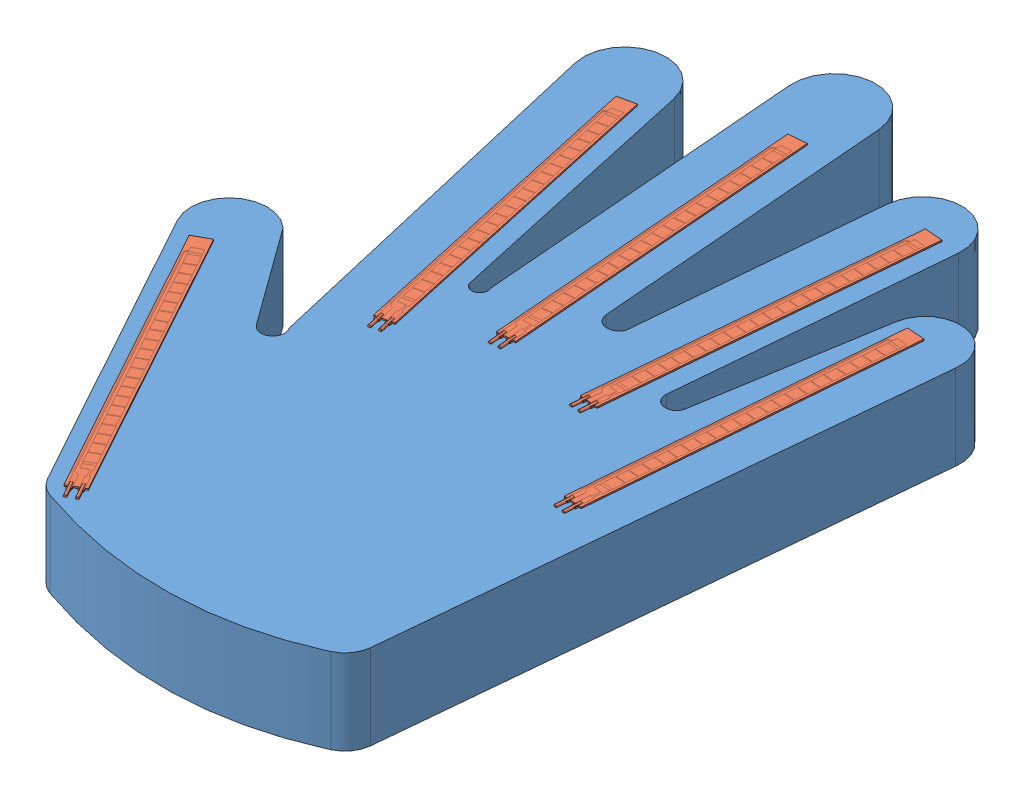
SolidWorks assembly Assem_glove, configuration Default. Lengths in mm.
Overall size (184.22 30.75 280.69).
6 component instances, 2 part files, 17 mates.
Components (placement in the parent):
- DPhand-1: DPhand [Default] at (75.3655 134.0465 341.8049) size (184.22 30 280.69)
- FLEX_SENSOR 115MM-2: FLEX_SENSOR 115MM [Default] at (72.6059 164.0465 175.982) x (-0.214556 0 -0.976712) z (0.976712 0 -0.214556) size (116.68 1 6.35)
- FLEX_SENSOR 115MM-3: FLEX_SENSOR 115MM [Default] at (107.0114 164.0465 158.7632) x (-0.080323 0 -0.996769) z (0.996769 0 -0.080323) size (116.68 1 6.35)
- FLEX_SENSOR 115MM-4: FLEX_SENSOR 115MM [Default] at (150.8006 164.0465 163.9826) x (0.088514 0 -0.996075) z (0.996075 0 0.088514) size (116.68 1 6.35)
- FLEX_SENSOR 115MM-5: FLEX_SENSOR 115MM [Default] at (178.2861 164.0465 197.4261) x (0.081658 0 -0.99666) z (0.99666 0 0.081658) size (116.68 1 6.35)
- FLEX_SENSOR 115MM-6: FLEX_SENSOR 115MM [Default] at (54.4712 164.0465 287.2629) x (-0.482154 0 -0.876087) z (0.876087 0 -0.482154) size (116.68 1 6.35)
Mates (geometry in assembly coordinates):
- Coincident21: coincident anti-aligned: plane of DPhand-1 through (131.1714 164.0465 351.9032) normal (0 1 0); plane of FLEX_SENSOR 115MM-2 through (72.6059 164.0465 175.982) normal (0 -1 0)
- Coincident22: coincident anti-aligned: line of FLEX_SENSOR 115MM-2 through (63.6661 164.0465 120.4877) axis (-0.976712 0 0.214556)
- Coincident23: coincident anti-aligned: line of FLEX_SENSOR 115MM-2 through (87.7479 164.0465 230.1138) axis (-0.214556 0 -0.976712)
- Coincident24: coincident anti-aligned: plane of DPhand-1 through (131.1714 164.0465 351.9032) normal (0 1 0); plane of FLEX_SENSOR 115MM-3 through (107.0114 164.0465 158.7632) normal (0 -1 0)
- Coincident30: coincident anti-aligned: line of FLEX_SENSOR 115MM-3 through (105.6684 164.0465 102.5695) axis (-0.996769 0 0.080323)
- Coincident31: coincident anti-aligned: line of FLEX_SENSOR 115MM-3 through (114.6839 164.0465 214.4468) axis (-0.080323 0 -0.996769)
- Coincident32: coincident anti-aligned: plane of DPhand-1 through (131.1714 164.0465 351.9032) normal (0 1 0); plane of FLEX_SENSOR 115MM-4 through (150.8006 164.0465 163.9826) normal (0 -1 0)
- Coincident33: coincident anti-aligned: line of FLEX_SENSOR 115MM-4 through (158.9306 164.0465 108.3639) axis (-0.996075 0 -0.088514)
- Coincident34: coincident anti-aligned: line of FLEX_SENSOR 115MM-4 through (148.9957 164.0465 220.1634) axis (0.088514 0 -0.996075)
- Coincident35: coincident anti-aligned: plane of DPhand-1 through (131.1714 164.0465 351.9032) normal (0 1 0); plane of FLEX_SENSOR 115MM-5 through (178.2861 164.0465 197.4261) normal (0 -1 0)
- Coincident38: coincident anti-aligned: line of FLEX_SENSOR 115MM-5 through (186.0332 164.0465 141.7528) axis (-0.99666 0 -0.081658)
- Coincident42: coincident aligned: line of FLEX_SENSOR 115MM-5 through (179.7044 164.0465 141.2343) axis (-0.081658 0 0.99666)
- Coincident43: coincident anti-aligned: plane of DPhand-1 through (131.1714 164.0465 351.9032) normal (0 1 0); plane of FLEX_SENSOR 115MM-6 through (54.4712 164.0465 287.2629) normal (0 -1 0)
- Parallel24: parallel anti-aligned: line of FLEX_SENSOR 115MM-6 through (84.3113 164.5465 334.8981) axis (-0.482154 0 -0.876087)
- Coincident53: coincident anti-aligned: line of FLEX_SENSOR 115MM-6 through (30.1944 164.0465 236.5661) axis (-0.876087 0 0.482154)
- Coincident54: coincident anti-aligned: plane of DPhand-1 through (131.1714 164.0465 351.9032) normal (0 1 0); plane of FLEX_SENSOR 115MM-6 through (54.4712 164.0465 287.2629) normal (0 -1 0)
- Coincident55: coincident aligned: line of FLEX_SENSOR 115MM-6 through (24.6312 164.0465 239.6278) axis (0.482154 0 0.876087)
